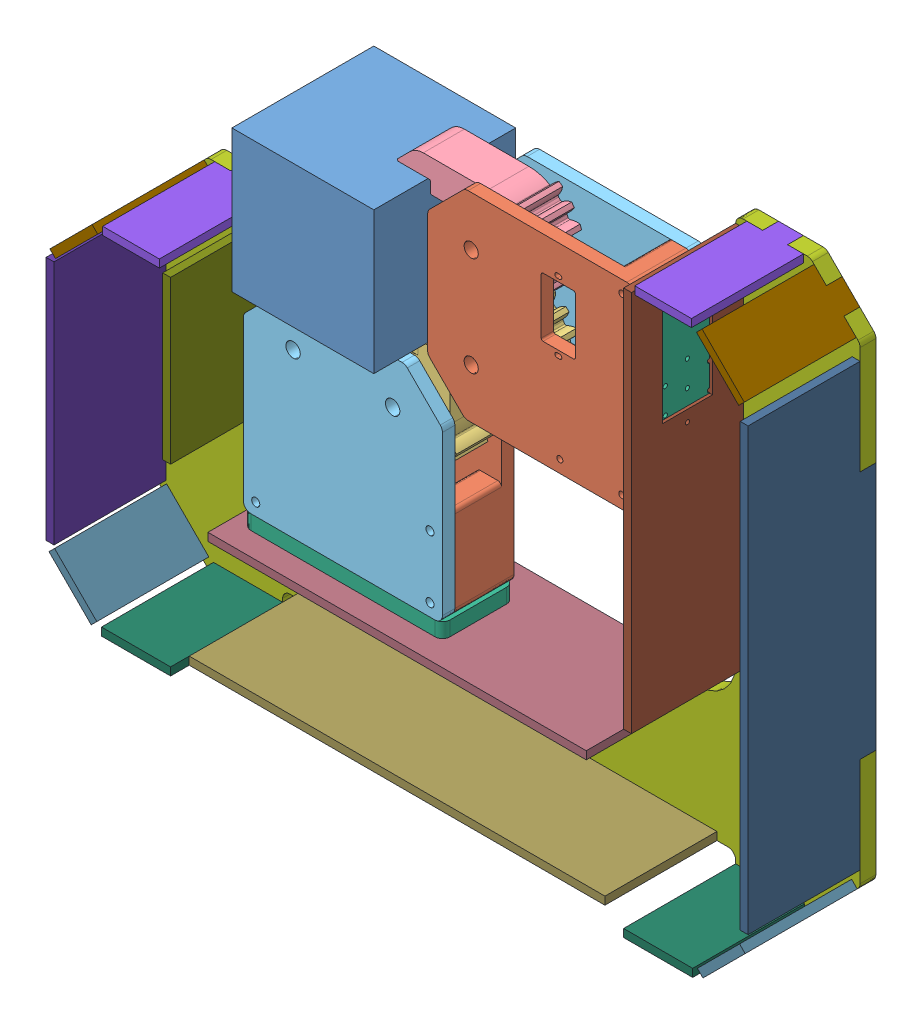
SolidWorks assembly master_v1, configuration Default. Lengths in mm.
Overall size (282 230.72 57.7).
61 component instances, 24 part files, 19 mates.
Components (placement in the parent):
- clasper_proto1-1: clasper_proto1 [Default] at (-14.375 -45.2758 0) x (0 -1 0) z (1 0 0) size (119.31 92.21 28.75) (hidden)
  - Servo_Mount-2: Servo_Mount [Default] at origin size (83 80 23.75)
  - Clasper_B2-1: Clasper_B2 [Default] at (-41.6324 -8.2383 21.5) x (0.974569 -0.224088 0) z (0 0 -1) size (66 44 18) (hidden)
  - Servo_Mount_lid-1: Servo_Mount_lid [Default] at (0.7242 0 23.75) size (64.5 81 5) (hidden)
  - Finger_GearAv2-1: Finger_GearAv2 [Default] at (-22.2758 20 14.9) x (-1 0 0) z (0 0 -1) size (58.15 43.7 18.15)
  - Finger_GearBv3-1: Finger_GearBv3 [Default] at (-22.2758 -20 14.9) x (-1 0 0) z (0 0 1) size (58.29 43.85 18.15)
  - Driving_Gears-1: Driving_Gears [Default] at (12.7242 -20 18.9201) x (-0.744653 0.667452 0) z (0 0 1) size (43 43 7.5) (hidden)
  - Servo_Mount_lidv2-1: Servo_Mount_lidv2 [Default] at (0 0 23.75) size (83 80 5)
  - servowristv2-1: servowristv2 [Default] at (43.2242 0 14.375) x (1 0 0) z (0 1 0) size (6 28.75 80)
  - stepperwrist-1: stepperwrist [Default] at (43.2242 0 14.375) x (1 0 0) z (0 1 0) size (6 28.75 80) (hidden)
- cube-1: cube [Default] at origin size (57 57 57)
- clasper_proto1-2: clasper_proto1 [Default] at (73.7758 14.125 0) x (1 0 0) z (0 1 0) size (119.31 92.21 28.75) (hidden)
  - Servo_Mount-2: Servo_Mount [Default] at origin size (83 80 23.75)
  - Clasper_B2-1: Clasper_B2 [Default] at (-41.6324 -8.2383 21.5) x (0.974569 -0.224088 0) z (0 0 -1) size (66 44 18) (hidden)
  - Servo_Mount_lid-1: Servo_Mount_lid [Default] at (0.7242 0 23.75) size (64.5 81 5) (hidden)
  - Finger_GearAv2-1: Finger_GearAv2 [Default] at (-22.2758 20 14.9) x (-1 0 0) z (0 0 -1) size (58.15 43.7 18.15)
  - Finger_GearBv3-1: Finger_GearBv3 [Default] at (-22.2758 -20 14.9) x (-1 0 0) z (0 0 1) size (58.29 43.85 18.15)
  - Driving_Gears-1: Driving_Gears [Default] at (12.7242 -20 18.9201) x (-0.744653 0.667452 0) z (0 0 1) size (43 43 7.5) (hidden)
  - Servo_Mount_lidv2-1: Servo_Mount_lidv2 [Default] at (0 0 23.75) size (83 80 5)
  - servowristv2-1: servowristv2 [Default] at (43.2242 0 14.375) x (1 0 0) z (0 1 0) size (6 28.75 80)
  - stepperwrist-1: stepperwrist [Default] at (43.2242 0 14.375) x (1 0 0) z (0 1 0) size (6 28.75 80) (hidden)
- dummy_housing-1: dummy_housing [Default] at (125.1535 -96.9942 -30) size (200 200 60) (hidden)
- clasper_proto1-3: clasper_proto1 [Default] at (75.7772 28.5 14.375) x (1 0 0) z (0 0 -1) size (119.31 92.21 28.75)
  - Servo_Mount-2: Servo_Mount [Default] at origin size (83 80 23.75)
  - Clasper_B2-1: Clasper_B2 [Default] at (-41.6324 -8.2383 21.5) x (0.974569 -0.224088 0) z (0 0 -1) size (66 44 18) (hidden)
  - Servo_Mount_lid-1: Servo_Mount_lid [Default] at (0.7242 0 23.75) size (64.5 81 5) (hidden)
  - Finger_GearAv2-1: Finger_GearAv2 [Default] at (-22.2758 20 14.9) x (-1 0 0) z (0 0 -1) size (58.15 43.7 18.15)
  - Finger_GearBv3-1: Finger_GearBv3 [Default] at (-22.2758 -20 14.9) x (-1 0 0) z (0 0 1) size (58.29 43.85 18.15)
  - Driving_Gears-1: Driving_Gears [Default] at (12.7242 -20 18.9201) x (-0.744653 0.667452 0) z (0 0 1) size (43 43 7.5) (hidden)
  - Servo_Mount_lidv2-1: Servo_Mount_lidv2 [Default] at (0 0 23.75) size (83 80 5)
  - servowristv2-1: servowristv2 [Default] at (43.2242 0 14.375) x (1 0 0) z (0 1 0) size (6 28.75 80)
  - stepperwrist-1: stepperwrist [Default] at (43.2242 0 14.375) x (1 0 0) z (0 1 0) size (6 28.75 80) (hidden)
- housing_A-1: housing_A [Default] at (97.9914 -87.708 -30.1283) x (0 0 1) z (-1 0 0) size (57 174 174) (hidden)
- sidepanel-1: sidepanel [Default] at (32.825 -94.5 0.0061) size (282 229 6.35) (hidden)
- clasper_proto1-4: clasper_proto1 [Default] at (0.975 -45.2758 -15.35) x (0 -1 0) z (0 0 1) size (119.31 92.21 28.75)
  - Servo_Mount-2: Servo_Mount [Default] at origin size (83 80 23.75)
  - Clasper_B2-1: Clasper_B2 [Default] at (-41.6324 -8.2383 21.5) x (0.974569 -0.224088 0) z (0 0 -1) size (66 44 18) (hidden)
  - Servo_Mount_lid-1: Servo_Mount_lid [Default] at (0.7242 0 23.75) size (64.5 81 5) (hidden)
  - Finger_GearAv2-1: Finger_GearAv2 [Default] at (-22.2758 20 14.9) x (-1 0 0) z (0 0 -1) size (58.15 43.7 18.15)
  - Finger_GearBv3-1: Finger_GearBv3 [Default] at (-22.2758 -20 14.9) x (-1 0 0) z (0 0 1) size (58.29 43.85 18.15)
  - Driving_Gears-1: Driving_Gears [Default] at (12.7242 -20 18.9201) x (-0.744653 0.667452 0) z (0 0 1) size (43 43 7.5) (hidden)
  - Servo_Mount_lidv2-1: Servo_Mount_lidv2 [Default] at (0 0 23.75) size (83 80 5)
  - servowristv2-1: servowristv2 [Default] at (43.2242 0 14.375) x (1 0 0) z (0 1 0) size (6 28.75 80)
  - stepperwrist-1: stepperwrist [Default] at (43.2242 0 14.375) x (1 0 0) z (0 1 0) size (6 28.75 80) (hidden)
- housing_master-2: housing_master [Default] at (32 -94.362 -25.5271) size (282 229 57.7)
  - sidepanel-1: sidepanel [Default] at origin size (282 229 6.35)
  - pieceA-1: pieceA [Default] at (101.8787 168.325 25.675) x (0 0 -1) z (1 0 0) size (51.35 3.17 22.75)
  - pieceB-1: pieceB [Default] at (125.2194 162.7905 25.675) x (0 0 -1) z (0.707107 -0.707107 0) size (51.35 3.17 24)
  - pieceB-2: pieceB [Default] at (-127.4645 78.874 25.675) x (0 0 -1) z (-0.707107 -0.707107 0) size (51.35 3.17 24)
  - pieceA-2: pieceA [Default] at (-111.8787 82.1635 25.675) x (0 0 -1) z (1 0 0) size (51.35 3.17 22.75)
  - pieceD-1: pieceD [Default] at (141 7 25.675) x (0 0 -1) z (0 1 0) size (51.35 3.17 177)
  - pieceC-2: pieceC [Default] at (94.175 41.75 25.675) x (0 0 -1) z (0 1 0) size (51.35 3.17 153.5)
  - pieceF-1: pieceF [Default] at (-50 -50 25.675) x (0 0 -1) z (1 0 0) size (51.35 3.17 167)
  - pieceE-1: pieceE [Default] at (-50 -3.175 25.675) x (0 0 -1) z (1 0 0) size (51.35 3.17 152)
  - pieceG-1: pieceG [Default] at (127.8206 -50.6794 25.675) x (0 0 -1) z (0.707107 0.707107 0) size (51.35 3.17 24)
  - pieceH-1: pieceH [Default] at (99.875 -57.5 25.675) x (0 0 -1) z (1 0 0) size (51.35 3.17 27.75)
  - pieceG-2: pieceG [Default] at (-125.5756 -48.4343 25.675) x (0 0 -1) z (-0.707107 0.707107 0) size (51.35 3.17 24)
  - pieceH-2: pieceH [Default] at (-109.875 -57.5 25.675) x (0 0 -1) z (1 0 0) size (51.35 3.17 27.75)
  - pieceI-1: pieceI [Default] at (-94.175 68.6692 25.675) x (0 0 -1) z (0 -1 0) size (51.35 3.17 65)
  - pieceJ-1: pieceJ [Default] at (-141 33.9192 25.675) x (0 0 -1) z (0 -1 0) size (51.35 3.17 98.5)
  - housinglid-1: housinglid [Default] at (-2.5 0 51.35) size (277 221.5 6.35) (hidden)
Mates (geometry in assembly coordinates):
- Coincident2: coordinate: point of cube-1; point of assembly
- Width1: width anti-aligned: plane of clasper_proto1-1/Finger_GearBv3-1 through (8.775 0 29.5) normal (0 0 -1); plane of clasper_proto1-1/Finger_GearAv2-1 through (-7.725 -23 -29.5) normal (0 0 1); plane of cube-1 through (-28.5 57 28.5) normal (0 0 1); plane of cube-1 through (-28.5 57 -28.5) normal (0 0 -1)
- Symmetric1: symmetric aligned: plane of clasper_proto1-1/Finger_GearAv2-1 through (-7.725 0 -20) normal (0 1 0); plane of cube-1 through (0 0 0) normal (0 -1 0); plane of clasper_proto1-1/Finger_GearBv3-1 through (8.775 0 24.5) normal (0 1 0)
- Width2: width aligned: plane of cube-1 through (28.5 57 -28.5) normal (1 0 0); plane of cube-1 through (-28.5 57 -28.5) normal (-1 0 0); plane of clasper_proto1-1/Servo_Mount_lidv2-1 through (14.375 -45.2758 0) normal (1 0 0); plane of clasper_proto1-1/Servo_Mount-2 through (-14.375 -45.2758 0) normal (-1 0 0)
- Width3: width anti-aligned: plane of clasper_proto1-2/Finger_GearAv2-1 through (51.5 20.775 -29.5) normal (0 0 1); plane of clasper_proto1-2/Finger_GearBv3-1 through (28.5 37.275 29.5) normal (0 0 -1); plane of cube-1 through (-28.5 57 -28.5) normal (0 0 -1); plane of cube-1 through (-28.5 57 28.5) normal (0 0 1)
- Parallel2: parallel aligned: plane of cube-1 through (0 57 0) normal (0 1 0); plane of clasper_proto1-2/Servo_Mount_lidv2-1 through (73.7758 42.875 0) normal (0 1 0)
- Width4: width anti-aligned: plane of cube-1 through (0 0 0) normal (0 -1 0); plane of cube-1 through (0 57 0) normal (0 1 0); plane of clasper_proto1-2/Servo_Mount_lidv2-1 through (73.7758 42.875 0) normal (0 1 0); plane of clasper_proto1-2/Servo_Mount-2 through (73.7758 14.125 0) normal (0 -1 0)
- Coincident3: coincident anti-aligned: plane of cube-1 through (28.5 57 -28.5) normal (1 0 0); plane of clasper_proto1-2/Finger_GearBv3-1 through (28.5 37.275 24.5) normal (-1 0 0)
- Width5: width anti-aligned: plane of dummy_housing-1 through (125.1535 -96.9942 30) normal (0 0 1); plane of dummy_housing-1 through (125.1535 -96.9942 -30) normal (0 0 -1); plane of cube-1 through (-28.5 57 -28.5) normal (0 0 -1); plane of cube-1 through (-28.5 57 28.5) normal (0 0 1)
- Perpendicular1: perpendicular: plane of clasper_proto1-2/Servo_Mount_lidv2-1 through (73.7758 42.875 0) normal (0 1 0); plane of clasper_proto1-3/Servo_Mount_lidv2-1 through (75.7772 28.5 -14.375) normal (0 0 -1)
- Width6: width aligned: plane of clasper_proto1-3/Finger_GearAv2-1 through (53.5014 -1 7.725) normal (0 1 0); plane of clasper_proto1-3/Finger_GearBv3-1 through (30.5014 58 -8.775) normal (0 -1 0); plane of cube-1 through (0 57 0) normal (0 1 0); plane of cube-1 through (0 0 0) normal (0 -1 0)
- Width7: width aligned: plane of cube-1 through (-28.5 57 28.5) normal (0 0 1); plane of cube-1 through (-28.5 57 -28.5) normal (0 0 -1); plane of clasper_proto1-3/Servo_Mount-2 through (75.7772 28.5 14.375) normal (0 0 1); plane of clasper_proto1-3/Servo_Mount_lidv2-1 through (75.7772 28.5 -14.375) normal (0 0 -1)
- Coincident5: coincident: circle of clasper_proto1-1/servowristv2-1; point of sidepanel-1
- Parallel3: parallel aligned: plane of cube-1 through (-28.5 57 28.5) normal (0 0 1); plane of sidepanel-1 through (32.825 -94.5 3.1811) normal (0 0 1)
- Parallel4: parallel aligned: plane of cube-1 through (0 0 0) normal (0 -1 0); plane of sidepanel-1 through (123.825 -144.5 -3.1689) normal (0 -1 0)
- Perpendicular2: perpendicular: plane of clasper_proto1-1/Servo_Mount-2 through (-14.375 -45.2758 0) normal (-1 0 0); plane of clasper_proto1-4/Servo_Mount-2 through (0.975 -45.2758 -15.35) normal (0 0 -1)
- Parallel5: parallel aligned: plane of sidepanel-1 through (32.825 -94.5 3.1811) normal (0 0 1); plane of clasper_proto1-4/Servo_Mount_lidv2-1 through (0.975 -45.2758 13.4) normal (0 0 1)
- Coincident10: coincident aligned: circle of clasper_proto1-1/servowristv2-1; circle of clasper_proto1-4/servowristv2-1
- Coincident11: coincident: circle of clasper_proto1-2/servowristv2-1; point of housing_master-2/pieceC-2
